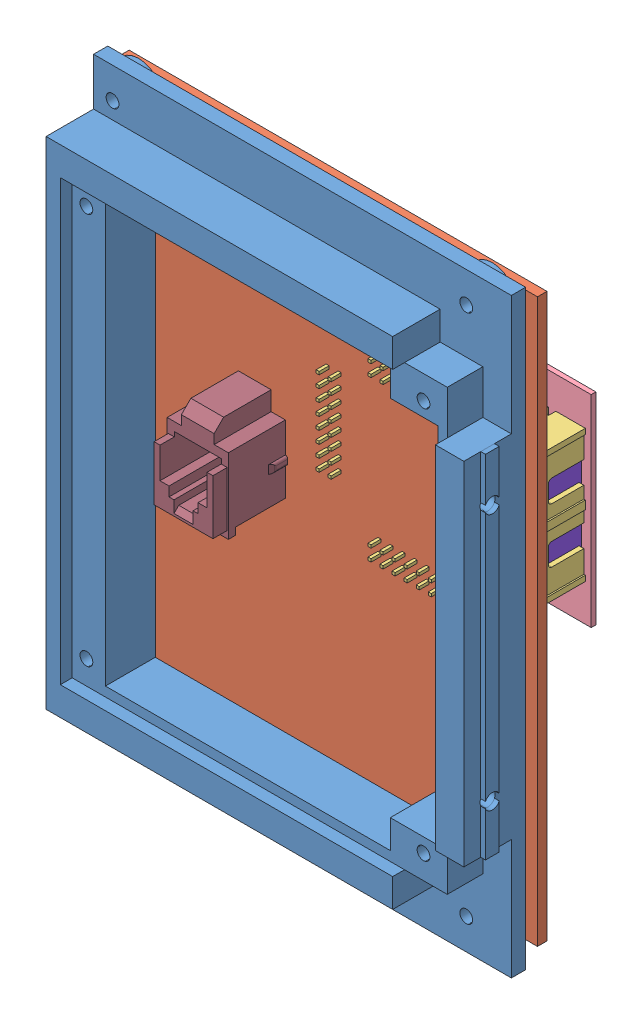
SolidWorks assembly MotorBoard32_WithSupport, configuration Default. Lengths in mm.
Overall size (90 124.5 31.41).
171 component instances, 13 part files, 3 mates.
Components (placement in the parent):
- MotorBoard32-Support-1: MotorBoard32-Support [Défaut] at (-63.0549 10.0438 21.1996) size (90 124.5 15.5)
- MotorBoard32-1: MotorBoard32 [Défaut] at (5.211 -52.348 136.6996) x (1 0 0) z (0 0 -1) size (88 118.5 30.91)
  - MotorBoard32-1: MotorBoard32 [Défaut] at (-68.2659 -62.3918 118) size (88 118.5 2)
  - Pic32Board-Chip-And-Support-1: Pic32Board-Chip-And-Support [Défaut] at (-34.6873 -76.3379 75.574) size (47.77 43.45 18)
    - Pic32Board-Support-1: Pic32Board-Support [Défaut] at (-7.1576 -16.2986 18.8481) size (46.79 42.79 12.9)
      - HE10-16Way-1: HE10-16Way [Default] at (-6.8205 -0.3878 34.3917) size (27.94 9.14 12.9)
      - HE10-16Way-3: HE10-16Way [Default] at (-6.8205 33.2562 34.3917) x (-1 0 0) z (0 0 1) size (27.94 9.14 12.9)
      - HE10-16Way-4: HE10-16Way [Default] at (12.2815 14.7142 34.3917) x (0 1 0) z (0 0 1) size (27.94 9.14 12.9)
      - HE10-16Way-5: HE10-16Way [Default] at (-25.3625 14.7142 34.3917) x (0 -1 0) z (0 0 1) size (27.94 9.14 12.9)
    - Pic32Board-1: Pic32Board [Défaut] at (-20.8201 0.0031 8.7398) x (-1 0 0) z (0 0 1) size (47 42.5 11.6)
      - Pic32Board-1: Pic32Board [Défaut] at (-29.7416 -22.193 46.5) size (47 42.5 1)
      - User Library-TQFP64-2-1: User Library-TQFP64-2 [Default] at (-6.3416 -0.843 48.025) x (1 0 0) z (0 -1 0) size (12.2 1.2 12.2)
        - User Library-TQFP64-2_Leg x0-27 y0-575 z1-0-1: User Library-TQFP64-2_Leg x0-27 y0-575 z1-0 [Default] at (-5.1 0 -1.25) x (0 0 1) z (-1 0 0) size (0.27 0.78 1)
        - User Library-TQFP64-2_Leg x0-27 y0-575 z1-0-2: User Library-TQFP64-2_Leg x0-27 y0-575 z1-0 [Default] at (-2.75 0 -5.1001) x (-1 0 0) z (0 0 -1) size (0.27 0.78 1)
        - User Library-TQFP64-2_Leg x0-27 y0-575 z1-0-3: User Library-TQFP64-2_Leg x0-27 y0-575 z1-0 [Default] at (-5.1 0 2.25) x (0 0 1) z (-1 0 0) size (0.27 0.78 1)
        - User Library-TQFP64-2_Leg x0-27 y0-575 z1-0-4: User Library-TQFP64-2_Leg x0-27 y0-575 z1-0 [Default] at (5.1 0 -3.25) x (0 0 -1) z (1 0 0) size (0.27 0.78 1)
        - User Library-TQFP64-2_Leg x0-27 y0-575 z1-0-5: User Library-TQFP64-2_Leg x0-27 y0-575 z1-0 [Default] at (-1.25 0 5.1001) size (0.27 0.78 1)
        - User Library-TQFP64-2_Leg x0-27 y0-575 z1-0-6: User Library-TQFP64-2_Leg x0-27 y0-575 z1-0 [Default] at (2.75 0 5.1001) size (0.27 0.78 1)
        - User Library-TQFP64-2_Leg x0-27 y0-575 z1-0-7: User Library-TQFP64-2_Leg x0-27 y0-575 z1-0 [Default] at (2.25 0 5.1001) size (0.27 0.78 1)
        - User Library-TQFP64-2_Leg x0-27 y0-575 z1-0-8: User Library-TQFP64-2_Leg x0-27 y0-575 z1-0 [Default] at (5.1 0 -0.25) x (0 0 -1) z (1 0 0) size (0.27 0.78 1)
        - User Library-TQFP64-2_Leg x0-27 y0-575 z1-0-9: User Library-TQFP64-2_Leg x0-27 y0-575 z1-0 [Default] at (-5.1 0 -0.75) x (0 0 1) z (-1 0 0) size (0.27 0.78 1)
        - User Library-TQFP64-2_Leg x0-27 y0-575 z1-0-10: User Library-TQFP64-2_Leg x0-27 y0-575 z1-0 [Default] at (2.25 0 -5.1001) x (-1 0 0) z (0 0 -1) size (0.27 0.78 1)
        - User Library-TQFP64-2_Leg x0-27 y0-575 z1-0-11: User Library-TQFP64-2_Leg x0-27 y0-575 z1-0 [Default] at (5.1 0 0.75) x (0 0 -1) z (1 0 0) size (0.27 0.78 1)
        - User Library-TQFP64-2_Leg x0-27 y0-575 z1-0-12: User Library-TQFP64-2_Leg x0-27 y0-575 z1-0 [Default] at (-0.25 0 -5.1001) x (-1 0 0) z (0 0 -1) size (0.27 0.78 1)
        - User Library-TQFP64-2_Leg x0-27 y0-575 z1-0-13: User Library-TQFP64-2_Leg x0-27 y0-575 z1-0 [Default] at (5.1 0 0.25) x (0 0 -1) z (1 0 0) size (0.27 0.78 1)
        - User Library-TQFP64-2_Leg x0-27 y0-575 z1-0-14: User Library-TQFP64-2_Leg x0-27 y0-575 z1-0 [Default] at (1.75 0 5.1001) size (0.27 0.78 1)
        - User Library-TQFP64-2_Leg x0-27 y0-575 z1-0-15: User Library-TQFP64-2_Leg x0-27 y0-575 z1-0 [Default] at (-1.25 0 -5.1001) x (-1 0 0) z (0 0 -1) size (0.27 0.78 1)
        - User Library-TQFP64-2_Leg x0-27 y0-575 z1-0-16: User Library-TQFP64-2_Leg x0-27 y0-575 z1-0 [Default] at (-5.1 0 1.75) x (0 0 1) z (-1 0 0) size (0.27 0.78 1)
        - User Library-TQFP64-2_Leg x0-27 y0-575 z1-0-17: User Library-TQFP64-2_Leg x0-27 y0-575 z1-0 [Default] at (3.25 0 5.1001) size (0.27 0.78 1)
        - User Library-TQFP64-2_Leg x0-27 y0-575 z1-0-18: User Library-TQFP64-2_Leg x0-27 y0-575 z1-0 [Default] at (2.75 0 -5.1001) x (-1 0 0) z (0 0 -1) size (0.27 0.78 1)
        - User Library-TQFP64-2_Leg x0-27 y0-575 z1-0-19: User Library-TQFP64-2_Leg x0-27 y0-575 z1-0 [Default] at (5.1 0 2.25) x (0 0 -1) z (1 0 0) size (0.27 0.78 1)
        - User Library-TQFP64-2_Leg x0-27 y0-575 z1-0-20: User Library-TQFP64-2_Leg x0-27 y0-575 z1-0 [Default] at (-3.25 0 -5.1001) x (-1 0 0) z (0 0 -1) size (0.27 0.78 1)
        - User Library-TQFP64-2_Leg x0-27 y0-575 z1-0-21: User Library-TQFP64-2_Leg x0-27 y0-575 z1-0 [Default] at (-3.75 0 5.1001) size (0.27 0.78 1)
        - User Library-TQFP64-2_Leg x0-27 y0-575 z1-0-22: User Library-TQFP64-2_Leg x0-27 y0-575 z1-0 [Default] at (-3.25 0 5.1001) size (0.27 0.78 1)
        - User Library-TQFP64-2_Leg x0-27 y0-575 z1-0-23: User Library-TQFP64-2_Leg x0-27 y0-575 z1-0 [Default] at (3.75 0 5.1001) size (0.27 0.78 1)
        - User Library-TQFP64-2_Leg x0-27 y0-575 z1-0-24: User Library-TQFP64-2_Leg x0-27 y0-575 z1-0 [Default] at (-5.1 0 0.25) x (0 0 1) z (-1 0 0) size (0.27 0.78 1)
        - User Library-TQFP64-2_Leg x0-27 y0-575 z1-0-25: User Library-TQFP64-2_Leg x0-27 y0-575 z1-0 [Default] at (5.1 0 3.25) x (0 0 -1) z (1 0 0) size (0.27 0.78 1)
        - User Library-TQFP64-2_Leg x0-27 y0-575 z1-0-26: User Library-TQFP64-2_Leg x0-27 y0-575 z1-0 [Default] at (-5.1 0 0.75) x (0 0 1) z (-1 0 0) size (0.27 0.78 1)
        - User Library-TQFP64-2_Leg x0-27 y0-575 z1-0-27: User Library-TQFP64-2_Leg x0-27 y0-575 z1-0 [Default] at (0.75 0 -5.1001) x (-1 0 0) z (0 0 -1) size (0.27 0.78 1)
        - User Library-TQFP64-2_Leg x0-27 y0-575 z1-0-28: User Library-TQFP64-2_Leg x0-27 y0-575 z1-0 [Default] at (5.1 0 1.75) x (0 0 -1) z (1 0 0) size (0.27 0.78 1)
        - User Library-TQFP64-2_Leg x0-27 y0-575 z1-0-29: User Library-TQFP64-2_Leg x0-27 y0-575 z1-0 [Default] at (-5.1 0 -3.75) x (0 0 1) z (-1 0 0) size (0.27 0.78 1)
        - User Library-TQFP64-2_Leg x0-27 y0-575 z1-0-30: User Library-TQFP64-2_Leg x0-27 y0-575 z1-0 [Default] at (5.1 0 -0.75) x (0 0 -1) z (1 0 0) size (0.27 0.78 1)
        - User Library-TQFP64-2_Leg x0-27 y0-575 z1-0-31: User Library-TQFP64-2_Leg x0-27 y0-575 z1-0 [Default] at (5.1 0 3.75) x (0 0 -1) z (1 0 0) size (0.27 0.78 1)
        - User Library-TQFP64-2_Leg x0-27 y0-575 z1-0-32: User Library-TQFP64-2_Leg x0-27 y0-575 z1-0 [Default] at (-2.25 0 5.1001) size (0.27 0.78 1)
        - User Library-TQFP64-2_Leg x0-27 y0-575 z1-0-33: User Library-TQFP64-2_Leg x0-27 y0-575 z1-0 [Default] at (-5.1 0 -3.25) x (0 0 1) z (-1 0 0) size (0.27 0.78 1)
        - User Library-TQFP64-2_Leg x0-27 y0-575 z1-0-34: User Library-TQFP64-2_Leg x0-27 y0-575 z1-0 [Default] at (-5.1 0 2.75) x (0 0 1) z (-1 0 0) size (0.27 0.78 1)
        - User Library-TQFP64-2_Leg x0-27 y0-575 z1-0-35: User Library-TQFP64-2_Leg x0-27 y0-575 z1-0 [Default] at (-5.1 0 3.75) x (0 0 1) z (-1 0 0) size (0.27 0.78 1)
        - User Library-TQFP64-2_Leg x0-27 y0-575 z1-0-36: User Library-TQFP64-2_Leg x0-27 y0-575 z1-0 [Default] at (1.25 0 -5.1001) x (-1 0 0) z (0 0 -1) size (0.27 0.78 1)
        - User Library-TQFP64-2_Leg x0-27 y0-575 z1-0-37: User Library-TQFP64-2_Leg x0-27 y0-575 z1-0 [Default] at (1.25 0 5.1001) size (0.27 0.78 1)
        - User Library-TQFP64-2_Leg x0-27 y0-575 z1-0-38: User Library-TQFP64-2_Leg x0-27 y0-575 z1-0 [Default] at (5.1 0 1.25) x (0 0 -1) z (1 0 0) size (0.27 0.78 1)
        - User Library-TQFP64-2_Leg x0-27 y0-575 z1-0-39: User Library-TQFP64-2_Leg x0-27 y0-575 z1-0 [Default] at (0.75 0 5.1001) size (0.27 0.78 1)
        - User Library-TQFP64-2_Leg x0-27 y0-575 z1-0-40: User Library-TQFP64-2_Leg x0-27 y0-575 z1-0 [Default] at (3.25 0 -5.1001) x (-1 0 0) z (0 0 -1) size (0.27 0.78 1)
        - User Library-TQFP64-2_Leg x0-27 y0-575 z1-0-41: User Library-TQFP64-2_Leg x0-27 y0-575 z1-0 [Default] at (-2.75 0 5.1001) size (0.27 0.78 1)
        - User Library-TQFP64-2_Leg x0-27 y0-575 z1-0-42: User Library-TQFP64-2_Leg x0-27 y0-575 z1-0 [Default] at (3.75 0 -5.1001) x (-1 0 0) z (0 0 -1) size (0.27 0.78 1)
        - User Library-TQFP64-2_Leg x0-27 y0-575 z1-0-43: User Library-TQFP64-2_Leg x0-27 y0-575 z1-0 [Default] at (1.75 0 -5.1001) x (-1 0 0) z (0 0 -1) size (0.27 0.78 1)
        - User Library-TQFP64-2_Leg x0-27 y0-575 z1-0-44: User Library-TQFP64-2_Leg x0-27 y0-575 z1-0 [Default] at (-5.1 0 -2.75) x (0 0 1) z (-1 0 0) size (0.27 0.78 1)
        - User Library-TQFP64-2_Leg x0-27 y0-575 z1-0-45: User Library-TQFP64-2_Leg x0-27 y0-575 z1-0 [Default] at (5.1 0 -2.25) x (0 0 -1) z (1 0 0) size (0.27 0.78 1)
        - User Library-TQFP64-2_Leg x0-27 y0-575 z1-0-46: User Library-TQFP64-2_Leg x0-27 y0-575 z1-0 [Default] at (-2.25 0 -5.1001) x (-1 0 0) z (0 0 -1) size (0.27 0.78 1)
        - User Library-TQFP64-2_Leg x0-27 y0-575 z1-0-47: User Library-TQFP64-2_Leg x0-27 y0-575 z1-0 [Default] at (-5.1 0 1.25) x (0 0 1) z (-1 0 0) size (0.27 0.78 1)
        - User Library-TQFP64-2_Leg x0-27 y0-575 z1-0-48: User Library-TQFP64-2_Leg x0-27 y0-575 z1-0 [Default] at (5.1 0 -3.75) x (0 0 -1) z (1 0 0) size (0.27 0.78 1)
        - User Library-TQFP64-2_Leg x0-27 y0-575 z1-0-49: User Library-TQFP64-2_Leg x0-27 y0-575 z1-0 [Default] at (0.25 0 -5.1001) x (-1 0 0) z (0 0 -1) size (0.27 0.78 1)
        - User Library-TQFP64-2_Leg x0-27 y0-575 z1-0-50: User Library-TQFP64-2_Leg x0-27 y0-575 z1-0 [Default] at (-3.75 0 -5.1001) x (-1 0 0) z (0 0 -1) size (0.27 0.78 1)
        - User Library-TQFP64-2_Leg x0-27 y0-575 z1-0-51: User Library-TQFP64-2_Leg x0-27 y0-575 z1-0 [Default] at (-5.1 0 -0.25) x (0 0 1) z (-1 0 0) size (0.27 0.78 1)
        - User Library-TQFP64-2_Leg x0-27 y0-575 z1-0-52: User Library-TQFP64-2_Leg x0-27 y0-575 z1-0 [Default] at (-0.75 0 5.1001) size (0.27 0.78 1)
        - User Library-TQFP64-2_Leg x0-27 y0-575 z1-0-53: User Library-TQFP64-2_Leg x0-27 y0-575 z1-0 [Default] at (5.1 0 -1.75) x (0 0 -1) z (1 0 0) size (0.27 0.78 1)
        - User Library-TQFP64-2_Leg x0-27 y0-575 z1-0-54: User Library-TQFP64-2_Leg x0-27 y0-575 z1-0 [Default] at (-5.1 0 -2.25) x (0 0 1) z (-1 0 0) size (0.27 0.78 1)
        - User Library-TQFP64-2_Leg x0-27 y0-575 z1-0-55: User Library-TQFP64-2_Leg x0-27 y0-575 z1-0 [Default] at (-0.75 0 -5.1001) x (-1 0 0) z (0 0 -1) size (0.27 0.78 1)
        - User Library-TQFP64-2_Leg x0-27 y0-575 z1-0-56: User Library-TQFP64-2_Leg x0-27 y0-575 z1-0 [Default] at (-5.1 0 3.25) x (0 0 1) z (-1 0 0) size (0.27 0.78 1)
        - User Library-TQFP64-2_Body x10-2 y10-2 z1-05-1: User Library-TQFP64-2_Body x10-2 y10-2 z1-05 [Default] at origin size (10.2 1.05 10.2)
        - User Library-TQFP64-2_Leg x0-27 y0-575 z1-0-57: User Library-TQFP64-2_Leg x0-27 y0-575 z1-0 [Default] at (0.25 0 5.1001) size (0.27 0.78 1)
        - User Library-TQFP64-2_Leg x0-27 y0-575 z1-0-58: User Library-TQFP64-2_Leg x0-27 y0-575 z1-0 [Default] at (5.1 0 2.75) x (0 0 -1) z (1 0 0) size (0.27 0.78 1)
        - User Library-TQFP64-2_Leg x0-27 y0-575 z1-0-59: User Library-TQFP64-2_Leg x0-27 y0-575 z1-0 [Default] at (-1.75 0 -5.1001) x (-1 0 0) z (0 0 -1) size (0.27 0.78 1)
        - User Library-TQFP64-2_Leg x0-27 y0-575 z1-0-60: User Library-TQFP64-2_Leg x0-27 y0-575 z1-0 [Default] at (-5.1 0 -1.75) x (0 0 1) z (-1 0 0) size (0.27 0.78 1)
        - User Library-TQFP64-2_Leg x0-27 y0-575 z1-0-61: User Library-TQFP64-2_Leg x0-27 y0-575 z1-0 [Default] at (-0.25 0 5.1001) size (0.27 0.78 1)
        - User Library-TQFP64-2_Leg x0-27 y0-575 z1-0-62: User Library-TQFP64-2_Leg x0-27 y0-575 z1-0 [Default] at (-1.75 0 5.1001) size (0.27 0.78 1)
        - User Library-TQFP64-2_Leg x0-27 y0-575 z1-0-63: User Library-TQFP64-2_Leg x0-27 y0-575 z1-0 [Default] at (5.1 0 -2.75) x (0 0 -1) z (1 0 0) size (0.27 0.78 1)
        - User Library-TQFP64-2_Leg x0-27 y0-575 z1-0-64: User Library-TQFP64-2_Leg x0-27 y0-575 z1-0 [Default] at (5.1 0 -1.25) x (0 0 -1) z (1 0 0) size (0.27 0.78 1)
      - HE10-16Way-Female-1: HE10-16Way-Female [Défaut] at (-8.4334 -17.4128 55.4002) x (1 0 0) z (0 0 -1) size (20.92 5.68 11.6)
        - User Library-MULTICOMP 2214S-08SG-85-1: User Library-MULTICOMP 2214S-08SG-85 [Default] at (-3.5782 -0.0598 8.9002) size (10.46 5.68 11.6)
          - User Library-MULTICOMP 2214S-08SG-85_contact-1: User Library-MULTICOMP 2214S-08SG-85_contact [Default] at (-3.81 -1.07 0.9) x (1 0 0) z (0 -1 0) size (2 10 0.4)
          - User Library-MULTICOMP 2214S-08SG-85_contact-2: User Library-MULTICOMP 2214S-08SG-85_contact [Default] at (-3.81 1.47 0.9) x (1 0 0) z (0 -1 0) size (2 10 0.4)
          - User Library-MULTICOMP 2214S-08SG-85_contact-3: User Library-MULTICOMP 2214S-08SG-85_contact [Default] at (-1.27 -1.07 0.9) x (1 0 0) z (0 -1 0) size (2 10 0.4)
          - User Library-MULTICOMP 2214S-08SG-85_contact-4: User Library-MULTICOMP 2214S-08SG-85_contact [Default] at (-1.27 1.47 0.9) x (1 0 0) z (0 -1 0) size (2 10 0.4)
          - User Library-MULTICOMP 2214S-08SG-85_contact-5: User Library-MULTICOMP 2214S-08SG-85_contact [Default] at (1.27 1.47 0.9) x (1 0 0) z (0 -1 0) size (2 10 0.4)
          - User Library-MULTICOMP 2214S-08SG-85_contact-6: User Library-MULTICOMP 2214S-08SG-85_contact [Default] at (1.27 -1.07 0.9) x (1 0 0) z (0 -1 0) size (2 10 0.4)
          - User Library-MULTICOMP 2214S-08SG-85_contact-7: User Library-MULTICOMP 2214S-08SG-85_contact [Default] at (3.81 -1.47 0.9) x (-1 0 0) z (0 1 0) size (2 10 0.4)
          - User Library-MULTICOMP 2214S-08SG-85_contact-8: User Library-MULTICOMP 2214S-08SG-85_contact [Default] at (3.81 1.07 0.9) x (-1 0 0) z (0 1 0) size (2 10 0.4)
          - User Library-MULTICOMP 2214S-08SG-85_housing-1: User Library-MULTICOMP 2214S-08SG-85_housing [Default] at origin size (10.46 5.68 8.5)
        - User Library-MULTICOMP 2214S-08SG-85-2: User Library-MULTICOMP 2214S-08SG-85 [Default] at (6.8818 -0.0598 8.9002) size (10.46 5.68 11.6)
          - User Library-MULTICOMP 2214S-08SG-85_contact-1: User Library-MULTICOMP 2214S-08SG-85_contact [Default] at (-3.81 -1.07 0.9) x (1 0 0) z (0 -1 0) size (2 10 0.4)
          - User Library-MULTICOMP 2214S-08SG-85_contact-2: User Library-MULTICOMP 2214S-08SG-85_contact [Default] at (-3.81 1.47 0.9) x (1 0 0) z (0 -1 0) size (2 10 0.4)
          - User Library-MULTICOMP 2214S-08SG-85_contact-3: User Library-MULTICOMP 2214S-08SG-85_contact [Default] at (-1.27 -1.07 0.9) x (1 0 0) z (0 -1 0) size (2 10 0.4)
          - User Library-MULTICOMP 2214S-08SG-85_contact-4: User Library-MULTICOMP 2214S-08SG-85_contact [Default] at (-1.27 1.47 0.9) x (1 0 0) z (0 -1 0) size (2 10 0.4)
          - User Library-MULTICOMP 2214S-08SG-85_contact-5: User Library-MULTICOMP 2214S-08SG-85_contact [Default] at (1.27 1.47 0.9) x (1 0 0) z (0 -1 0) size (2 10 0.4)
          - User Library-MULTICOMP 2214S-08SG-85_contact-6: User Library-MULTICOMP 2214S-08SG-85_contact [Default] at (1.27 -1.07 0.9) x (1 0 0) z (0 -1 0) size (2 10 0.4)
          - User Library-MULTICOMP 2214S-08SG-85_contact-7: User Library-MULTICOMP 2214S-08SG-85_contact [Default] at (3.81 -1.47 0.9) x (-1 0 0) z (0 1 0) size (2 10 0.4)
          - User Library-MULTICOMP 2214S-08SG-85_contact-8: User Library-MULTICOMP 2214S-08SG-85_contact [Default] at (3.81 1.07 0.9) x (-1 0 0) z (0 1 0) size (2 10 0.4)
          - User Library-MULTICOMP 2214S-08SG-85_housing-1: User Library-MULTICOMP 2214S-08SG-85_housing [Default] at origin size (10.46 5.68 8.5)
      - HE10-16Way-Female-2: HE10-16Way-Female [Défaut] at (-8.4334 16.0872 55.4002) x (1 0 0) z (0 0 -1) size (20.92 5.68 11.6)
        - User Library-MULTICOMP 2214S-08SG-85-1: User Library-MULTICOMP 2214S-08SG-85 [Default] at (-3.5782 -0.0598 8.9002) size (10.46 5.68 11.6)
          - User Library-MULTICOMP 2214S-08SG-85_contact-1: User Library-MULTICOMP 2214S-08SG-85_contact [Default] at (-3.81 -1.07 0.9) x (1 0 0) z (0 -1 0) size (2 10 0.4)
          - User Library-MULTICOMP 2214S-08SG-85_contact-2: User Library-MULTICOMP 2214S-08SG-85_contact [Default] at (-3.81 1.47 0.9) x (1 0 0) z (0 -1 0) size (2 10 0.4)
          - User Library-MULTICOMP 2214S-08SG-85_contact-3: User Library-MULTICOMP 2214S-08SG-85_contact [Default] at (-1.27 -1.07 0.9) x (1 0 0) z (0 -1 0) size (2 10 0.4)
          - User Library-MULTICOMP 2214S-08SG-85_contact-4: User Library-MULTICOMP 2214S-08SG-85_contact [Default] at (-1.27 1.47 0.9) x (1 0 0) z (0 -1 0) size (2 10 0.4)
          - User Library-MULTICOMP 2214S-08SG-85_contact-5: User Library-MULTICOMP 2214S-08SG-85_contact [Default] at (1.27 1.47 0.9) x (1 0 0) z (0 -1 0) size (2 10 0.4)
          - User Library-MULTICOMP 2214S-08SG-85_contact-6: User Library-MULTICOMP 2214S-08SG-85_contact [Default] at (1.27 -1.07 0.9) x (1 0 0) z (0 -1 0) size (2 10 0.4)
          - User Library-MULTICOMP 2214S-08SG-85_contact-7: User Library-MULTICOMP 2214S-08SG-85_contact [Default] at (3.81 -1.47 0.9) x (-1 0 0) z (0 1 0) size (2 10 0.4)
          - User Library-MULTICOMP 2214S-08SG-85_contact-8: User Library-MULTICOMP 2214S-08SG-85_contact [Default] at (3.81 1.07 0.9) x (-1 0 0) z (0 1 0) size (2 10 0.4)
          - User Library-MULTICOMP 2214S-08SG-85_housing-1: User Library-MULTICOMP 2214S-08SG-85_housing [Default] at origin size (10.46 5.68 8.5)
        - User Library-MULTICOMP 2214S-08SG-85-2: User Library-MULTICOMP 2214S-08SG-85 [Default] at (6.8818 -0.0598 8.9002) size (10.46 5.68 11.6)
          - User Library-MULTICOMP 2214S-08SG-85_contact-1: User Library-MULTICOMP 2214S-08SG-85_contact [Default] at (-3.81 -1.07 0.9) x (1 0 0) z (0 -1 0) size (2 10 0.4)
          - User Library-MULTICOMP 2214S-08SG-85_contact-2: User Library-MULTICOMP 2214S-08SG-85_contact [Default] at (-3.81 1.47 0.9) x (1 0 0) z (0 -1 0) size (2 10 0.4)
          - User Library-MULTICOMP 2214S-08SG-85_contact-3: User Library-MULTICOMP 2214S-08SG-85_contact [Default] at (-1.27 -1.07 0.9) x (1 0 0) z (0 -1 0) size (2 10 0.4)
          - User Library-MULTICOMP 2214S-08SG-85_contact-4: User Library-MULTICOMP 2214S-08SG-85_contact [Default] at (-1.27 1.47 0.9) x (1 0 0) z (0 -1 0) size (2 10 0.4)
          - User Library-MULTICOMP 2214S-08SG-85_contact-5: User Library-MULTICOMP 2214S-08SG-85_contact [Default] at (1.27 1.47 0.9) x (1 0 0) z (0 -1 0) size (2 10 0.4)
          - User Library-MULTICOMP 2214S-08SG-85_contact-6: User Library-MULTICOMP 2214S-08SG-85_contact [Default] at (1.27 -1.07 0.9) x (1 0 0) z (0 -1 0) size (2 10 0.4)
          - User Library-MULTICOMP 2214S-08SG-85_contact-7: User Library-MULTICOMP 2214S-08SG-85_contact [Default] at (3.81 -1.47 0.9) x (-1 0 0) z (0 1 0) size (2 10 0.4)
          - User Library-MULTICOMP 2214S-08SG-85_contact-8: User Library-MULTICOMP 2214S-08SG-85_contact [Default] at (3.81 1.07 0.9) x (-1 0 0) z (0 1 0) size (2 10 0.4)
          - User Library-MULTICOMP 2214S-08SG-85_housing-1: User Library-MULTICOMP 2214S-08SG-85_housing [Default] at origin size (10.46 5.68 8.5)
      - HE10-16Way-Female-3: HE10-16Way-Female [Défaut] at (-24.9614 2.4188 55.4002) x (0 -1 0) z (0 0 -1) size (20.92 5.68 11.6)
        - User Library-MULTICOMP 2214S-08SG-85-1: User Library-MULTICOMP 2214S-08SG-85 [Default] at (-3.5782 -0.0598 8.9002) size (10.46 5.68 11.6)
          - User Library-MULTICOMP 2214S-08SG-85_contact-1: User Library-MULTICOMP 2214S-08SG-85_contact [Default] at (-3.81 -1.07 0.9) x (1 0 0) z (0 -1 0) size (2 10 0.4)
          - User Library-MULTICOMP 2214S-08SG-85_contact-2: User Library-MULTICOMP 2214S-08SG-85_contact [Default] at (-3.81 1.47 0.9) x (1 0 0) z (0 -1 0) size (2 10 0.4)
          - User Library-MULTICOMP 2214S-08SG-85_contact-3: User Library-MULTICOMP 2214S-08SG-85_contact [Default] at (-1.27 -1.07 0.9) x (1 0 0) z (0 -1 0) size (2 10 0.4)
          - User Library-MULTICOMP 2214S-08SG-85_contact-4: User Library-MULTICOMP 2214S-08SG-85_contact [Default] at (-1.27 1.47 0.9) x (1 0 0) z (0 -1 0) size (2 10 0.4)
          - User Library-MULTICOMP 2214S-08SG-85_contact-5: User Library-MULTICOMP 2214S-08SG-85_contact [Default] at (1.27 1.47 0.9) x (1 0 0) z (0 -1 0) size (2 10 0.4)
          - User Library-MULTICOMP 2214S-08SG-85_contact-6: User Library-MULTICOMP 2214S-08SG-85_contact [Default] at (1.27 -1.07 0.9) x (1 0 0) z (0 -1 0) size (2 10 0.4)
          - User Library-MULTICOMP 2214S-08SG-85_contact-7: User Library-MULTICOMP 2214S-08SG-85_contact [Default] at (3.81 -1.47 0.9) x (-1 0 0) z (0 1 0) size (2 10 0.4)
          - User Library-MULTICOMP 2214S-08SG-85_contact-8: User Library-MULTICOMP 2214S-08SG-85_contact [Default] at (3.81 1.07 0.9) x (-1 0 0) z (0 1 0) size (2 10 0.4)
          - User Library-MULTICOMP 2214S-08SG-85_housing-1: User Library-MULTICOMP 2214S-08SG-85_housing [Default] at origin size (10.46 5.68 8.5)
        - User Library-MULTICOMP 2214S-08SG-85-2: User Library-MULTICOMP 2214S-08SG-85 [Default] at (6.8818 -0.0598 8.9002) size (10.46 5.68 11.6)
          - User Library-MULTICOMP 2214S-08SG-85_contact-1: User Library-MULTICOMP 2214S-08SG-85_contact [Default] at (-3.81 -1.07 0.9) x (1 0 0) z (0 -1 0) size (2 10 0.4)
          - User Library-MULTICOMP 2214S-08SG-85_contact-2: User Library-MULTICOMP 2214S-08SG-85_contact [Default] at (-3.81 1.47 0.9) x (1 0 0) z (0 -1 0) size (2 10 0.4)
          - User Library-MULTICOMP 2214S-08SG-85_contact-3: User Library-MULTICOMP 2214S-08SG-85_contact [Default] at (-1.27 -1.07 0.9) x (1 0 0) z (0 -1 0) size (2 10 0.4)
          - User Library-MULTICOMP 2214S-08SG-85_contact-4: User Library-MULTICOMP 2214S-08SG-85_contact [Default] at (-1.27 1.47 0.9) x (1 0 0) z (0 -1 0) size (2 10 0.4)
          - User Library-MULTICOMP 2214S-08SG-85_contact-5: User Library-MULTICOMP 2214S-08SG-85_contact [Default] at (1.27 1.47 0.9) x (1 0 0) z (0 -1 0) size (2 10 0.4)
          - User Library-MULTICOMP 2214S-08SG-85_contact-6: User Library-MULTICOMP 2214S-08SG-85_contact [Default] at (1.27 -1.07 0.9) x (1 0 0) z (0 -1 0) size (2 10 0.4)
          - User Library-MULTICOMP 2214S-08SG-85_contact-7: User Library-MULTICOMP 2214S-08SG-85_contact [Default] at (3.81 -1.47 0.9) x (-1 0 0) z (0 1 0) size (2 10 0.4)
          - User Library-MULTICOMP 2214S-08SG-85_contact-8: User Library-MULTICOMP 2214S-08SG-85_contact [Default] at (3.81 1.07 0.9) x (-1 0 0) z (0 1 0) size (2 10 0.4)
          - User Library-MULTICOMP 2214S-08SG-85_housing-1: User Library-MULTICOMP 2214S-08SG-85_housing [Default] at origin size (10.46 5.68 8.5)
      - HE10-16Way-Female-4: HE10-16Way-Female [Défaut] at (12.0386 2.4188 55.4002) x (0 -1 0) z (0 0 -1) size (20.92 5.68 11.6)
        - User Library-MULTICOMP 2214S-08SG-85-1: User Library-MULTICOMP 2214S-08SG-85 [Default] at (-3.5782 -0.0598 8.9002) size (10.46 5.68 11.6)
          - User Library-MULTICOMP 2214S-08SG-85_contact-1: User Library-MULTICOMP 2214S-08SG-85_contact [Default] at (-3.81 -1.07 0.9) x (1 0 0) z (0 -1 0) size (2 10 0.4)
          - User Library-MULTICOMP 2214S-08SG-85_contact-2: User Library-MULTICOMP 2214S-08SG-85_contact [Default] at (-3.81 1.47 0.9) x (1 0 0) z (0 -1 0) size (2 10 0.4)
          - User Library-MULTICOMP 2214S-08SG-85_contact-3: User Library-MULTICOMP 2214S-08SG-85_contact [Default] at (-1.27 -1.07 0.9) x (1 0 0) z (0 -1 0) size (2 10 0.4)
          - User Library-MULTICOMP 2214S-08SG-85_contact-4: User Library-MULTICOMP 2214S-08SG-85_contact [Default] at (-1.27 1.47 0.9) x (1 0 0) z (0 -1 0) size (2 10 0.4)
          - User Library-MULTICOMP 2214S-08SG-85_contact-5: User Library-MULTICOMP 2214S-08SG-85_contact [Default] at (1.27 1.47 0.9) x (1 0 0) z (0 -1 0) size (2 10 0.4)
          - User Library-MULTICOMP 2214S-08SG-85_contact-6: User Library-MULTICOMP 2214S-08SG-85_contact [Default] at (1.27 -1.07 0.9) x (1 0 0) z (0 -1 0) size (2 10 0.4)
          - User Library-MULTICOMP 2214S-08SG-85_contact-7: User Library-MULTICOMP 2214S-08SG-85_contact [Default] at (3.81 -1.47 0.9) x (-1 0 0) z (0 1 0) size (2 10 0.4)
          - User Library-MULTICOMP 2214S-08SG-85_contact-8: User Library-MULTICOMP 2214S-08SG-85_contact [Default] at (3.81 1.07 0.9) x (-1 0 0) z (0 1 0) size (2 10 0.4)
          - User Library-MULTICOMP 2214S-08SG-85_housing-1: User Library-MULTICOMP 2214S-08SG-85_housing [Default] at origin size (10.46 5.68 8.5)
        - User Library-MULTICOMP 2214S-08SG-85-2: User Library-MULTICOMP 2214S-08SG-85 [Default] at (6.8818 -0.0598 8.9002) size (10.46 5.68 11.6)
          - User Library-MULTICOMP 2214S-08SG-85_contact-1: User Library-MULTICOMP 2214S-08SG-85_contact [Default] at (-3.81 -1.07 0.9) x (1 0 0) z (0 -1 0) size (2 10 0.4)
          - User Library-MULTICOMP 2214S-08SG-85_contact-2: User Library-MULTICOMP 2214S-08SG-85_contact [Default] at (-3.81 1.47 0.9) x (1 0 0) z (0 -1 0) size (2 10 0.4)
          - User Library-MULTICOMP 2214S-08SG-85_contact-3: User Library-MULTICOMP 2214S-08SG-85_contact [Default] at (-1.27 -1.07 0.9) x (1 0 0) z (0 -1 0) size (2 10 0.4)
          - User Library-MULTICOMP 2214S-08SG-85_contact-4: User Library-MULTICOMP 2214S-08SG-85_contact [Default] at (-1.27 1.47 0.9) x (1 0 0) z (0 -1 0) size (2 10 0.4)
          - User Library-MULTICOMP 2214S-08SG-85_contact-5: User Library-MULTICOMP 2214S-08SG-85_contact [Default] at (1.27 1.47 0.9) x (1 0 0) z (0 -1 0) size (2 10 0.4)
          - User Library-MULTICOMP 2214S-08SG-85_contact-6: User Library-MULTICOMP 2214S-08SG-85_contact [Default] at (1.27 -1.07 0.9) x (1 0 0) z (0 -1 0) size (2 10 0.4)
          - User Library-MULTICOMP 2214S-08SG-85_contact-7: User Library-MULTICOMP 2214S-08SG-85_contact [Default] at (3.81 -1.47 0.9) x (-1 0 0) z (0 1 0) size (2 10 0.4)
          - User Library-MULTICOMP 2214S-08SG-85_contact-8: User Library-MULTICOMP 2214S-08SG-85_contact [Default] at (3.81 1.07 0.9) x (-1 0 0) z (0 1 0) size (2 10 0.4)
          - User Library-MULTICOMP 2214S-08SG-85_housing-1: User Library-MULTICOMP 2214S-08SG-85_housing [Default] at origin size (10.46 5.68 8.5)
  - User Library-molex kk 0_1in latching 5 way vertical header-1: User Library-molex kk 0_1in latching 5 way vertical header [Default] at (-108.3957 -32.9918 121.5875) x (0 1 0) z (1 0 0) size (12.7 15.24 5.84)
  - User Library-molex kk 0_1in latching 4 way vertical header-1: User Library-molex kk 0_1in latching 4 way vertical header [Default] at (-108.3957 -49.7218 121.5875) x (0 1 0) z (1 0 0) size (10.16 15.24 5.84)
  - User Library-molex kk 0_1in latching 4 way vertical header-2: User Library-molex kk 0_1in latching 4 way vertical header [Default] at (-108.3957 -61.2218 121.5875) x (0 1 0) z (1 0 0) size (10.16 15.24 5.84)
  - User Library-molex kk 0_1in latching 4 way vertical header-3: User Library-molex kk 0_1in latching 4 way vertical header [Default] at (-108.3957 -72.7218 121.5875) x (0 1 0) z (1 0 0) size (10.16 15.24 5.84)
  - User Library-molex kk 0_1in latching 4 way vertical header-4: User Library-molex kk 0_1in latching 4 way vertical header [Default] at (-108.3957 -84.2218 121.5875) x (0 1 0) z (1 0 0) size (10.16 15.24 5.84)
  - User Library-molex kk 0_1in latching 3 way vertical header-1: User Library-molex kk 0_1in latching 3 way vertical header [Default] at (-108.3957 -94.8318 121.5875) x (0 1 0) z (1 0 0) size (7.62 15.24 5.84)
  - User Library-molex kk 0_1in latching 3 way vertical header-2: User Library-molex kk 0_1in latching 3 way vertical header [Default] at (-108.3957 -106.3318 121.5875) x (0 1 0) z (1 0 0) size (7.62 15.24 5.84)
  - User Library-SMD Polymer Aluminum Electrolytic Capacitors F12 1500uF 2,5V-1: User Library-SMD Polymer Aluminum Electrolytic Capacitors F12 1500uF 2,5V [Default] at (-101.1159 -10.7918 120) size (11 10.3 11.15)
  - User Library-SMD Polymer Aluminum Electrolytic Capacitors F12 1500uF 2,5V-2: User Library-SMD Polymer Aluminum Electrolytic Capacitors F12 1500uF 2,5V [Default] at (-53.1159 -10.7918 120) size (11 10.3 11.15)
  - User Library-RJ11f-1: User Library-RJ11f [Default] at (-83.8159 -67.4918 118) x (1 0 0) z (0 0 -1) size (14.9 19.8 19)
Mates (geometry in assembly coordinates):
- Coaxiale1: concentric: cylinder of MotorBoard32-Support-1 through (-103.0549 65.7938 18.6996) axis (0 0 1) radius 1.35; cylinder of ? through (-103.0549 65.7938 18.6996) axis (0 0 -1) radius 2
- Coïncidente1: coincident: plane of MotorBoard32-Support-1 through (-103.0549 65.7938 18.6996) normal (0 0 -1); plane of ? through (-71.978 4.6196 18.6996) normal (0 0 1)
- Coaxiale2: concentric anti-aligned: cylinder of MotorBoard32-Support-1 through (-28.5549 65.7938 18.6996) axis (0 0 1) radius 1.35; cylinder of MotorBoard32-1/MotorBoard32-1 through (-28.5549 65.7938 18.6996) axis (0 0 -1) radius 2
